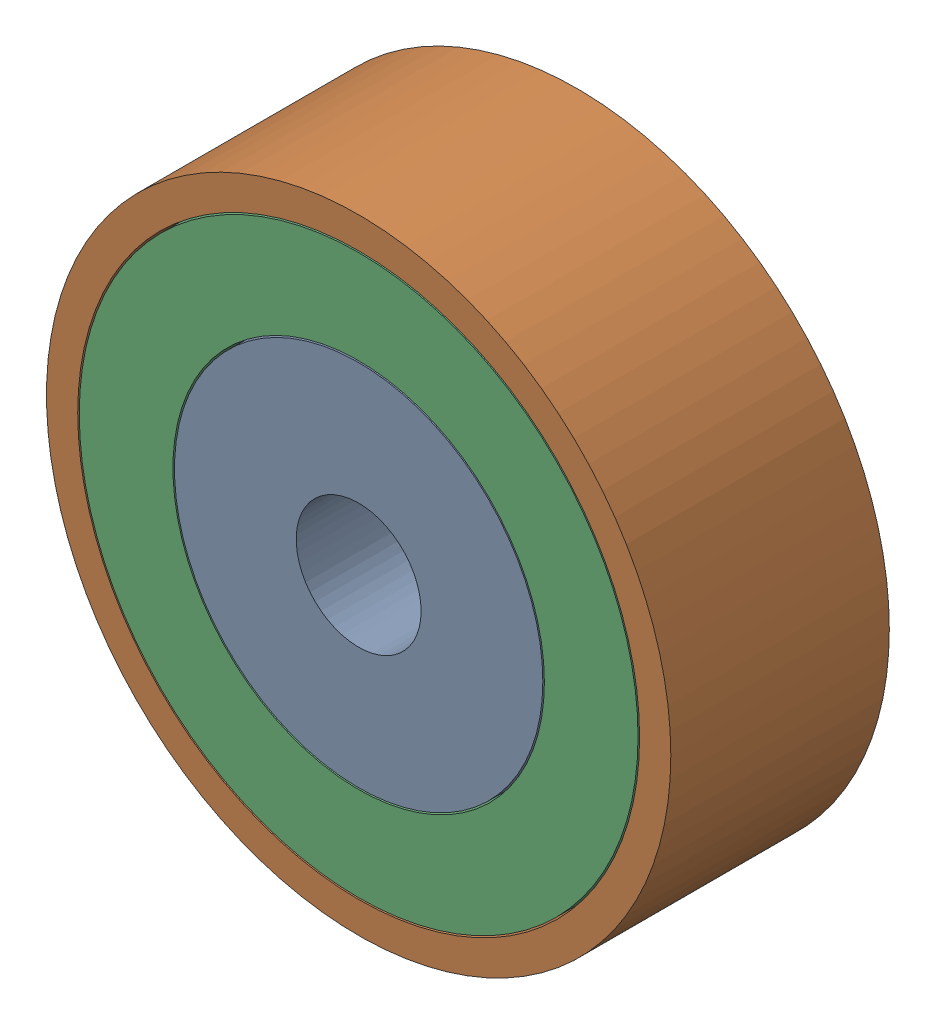
SolidWorks assembly 镜向轴承8, configuration 默认. Lengths in mm.
Overall size (20 20 7).
3 component instances, 3 part files, 4 mates.
Components (placement in the parent):
- 镜向轴承内圈-1: 镜向轴承内圈 [默认] at (-5.0655 0.8032 -6.5) size (11.8 11.8 7)
- 镜向轴承外圈-1: 镜向轴承外圈 [默认] at (-5.0655 0.8032 -6.5) size (20 20 7)
- 镜向轴承中圈-1: 镜向轴承中圈 [默认] at (-5.0655 0.8032 -6.5) size (17.9 17.9 7)
Mates (geometry in assembly coordinates):
- 重合1: coincident: plane of ? through (-5.0655 0.8032 -13.5) normal (0 0 -1); plane of ? through (-5.0655 0.8032 -13.5) normal (0 0 -1)
- 重合2: coincident: plane of ? through (-5.0655 0.8032 -13.5) normal (0 0 -1); plane of ? through (-5.0655 0.8032 -13.5) normal (0 0 -1)
- 同心1: concentric: cylinder of ? through (-5.0655 0.8032 -13.5) axis (0 0 1) radius 9; cylinder of ? through (-5.0655 0.8032 -13.5) axis (0 0 1) radius 8.95
- 同心2: concentric: cylinder of ? through (-5.0655 0.8032 -13.5) axis (0 0 1) radius 5.9; cylinder of ? through (-5.0655 0.8032 -13.5) axis (0 0 1) radius 5.95
